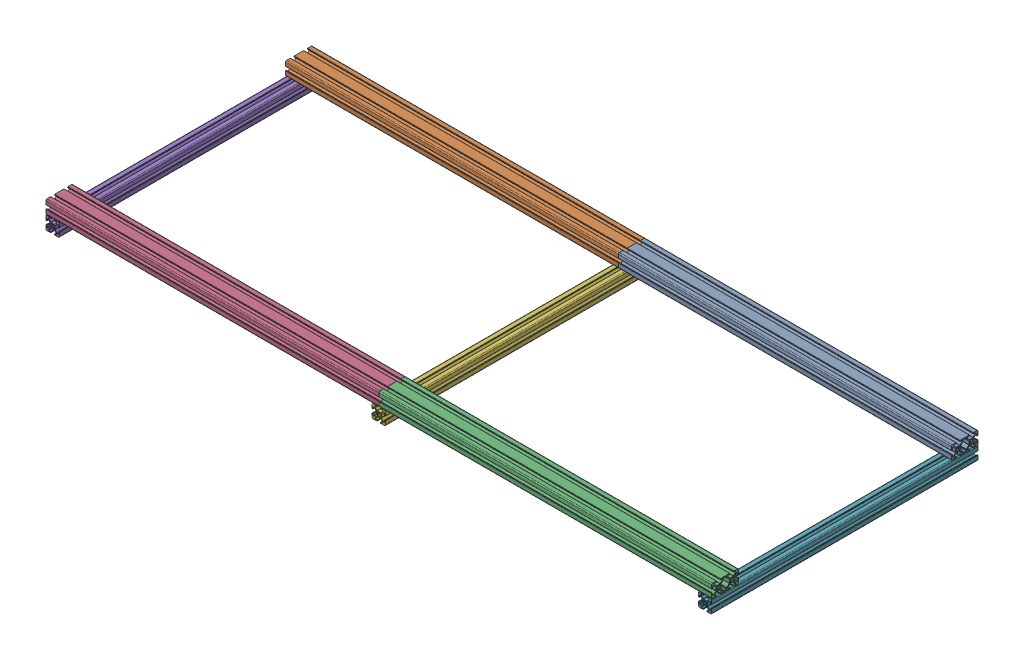
SolidWorks assembly BeltyV2-baseSubAssem, configuration Default. Lengths in mm.
Overall size (1000 40 400).
9 component instances, 2 part files, 16 mates.
Components (placement in the parent):
- BeltyV2-doubleSubAssem-1: BeltyV2-doubleSubAssem [Default] at (253.5332 30.8099 -182.4146) size (1000 20 40)
  - 2040-50-1: 2040-50 [Default] at (246.4668 -0.8099 2.4146) size (500 20 40)
  - 2040-50-2: 2040-50 [Default] at (-253.5332 -0.8099 2.4146) size (500 20 40)
- BeltyV2-doubleSubAssem-2: BeltyV2-doubleSubAssem [Default] at (253.5332 30.8099 177.5854) size (1000 20 40)
  - 2040-50-1: 2040-50 [Default] at (246.4668 -0.8099 2.4146) size (500 20 40)
  - 2040-50-2: 2040-50 [Default] at (-253.5332 -0.8099 2.4146) size (500 20 40)
- 2020-41-1: 2020-41 [Default] at (-490 10 200) x (0 0 1) z (-1 0 0) size (400 20 20)
- 2020-41-2: 2020-41 [Default] at (0 10 200) x (0 0 1) z (-1 0 0) size (400 20 20)
- 2020-41-3: 2020-41 [Default] at (490 10 -200) x (0 0 -1) z (0 1 0) size (400 20 20)
Mates (geometry in assembly coordinates):
- Coincident1: coincident aligned: plane of BeltyV2-doubleSubAssem-2/2040-50-2 through (0 35.819 74.8194) normal (0 0 1); plane of 2020-40-1 through (-490 10 74.8194) normal (0 0 1)
- Coincident2: coincident anti-aligned: plane of BeltyV2-doubleSubAssem-2/2040-50-2 through (0 20 54.8194) normal (0 -1 0); plane of 2020-40-1 through (-484.181 20 74.8194) normal (0 1 0)
- Coincident3: coincident aligned: plane of BeltyV2-doubleSubAssem-2/2040-50-2 through (-500 30 54.8194) normal (-1 0 0); plane of 2020-40-1 through (-500 15.819 74.8194) normal (-1 0 0)
- Coincident4: coincident aligned: plane of BeltyV2-doubleSubAssem-1/2040-50-2 through (-500 30 -305.1806) normal (-1 0 0); plane of 2020-40-1 through (-500 15.819 74.8194) normal (-1 0 0)
- Coincident5: coincident anti-aligned: plane of BeltyV2-doubleSubAssem-1/2040-50-2 through (0 20 -305.1806) normal (0 -1 0); plane of 2020-40-1 through (-495.819 20 74.8194) normal (0 1 0)
- Coincident6: coincident aligned: plane of BeltyV2-doubleSubAssem-1/2040-50-2 through (-500 30 -305.1806) normal (-1 0 0); plane of 2020-40-1 through (-500 15.819 74.8194) normal (-1 0 0)
- Coincident7: coincident aligned: plane of BeltyV2-doubleSubAssem-1/2040-50-2 through (0 24.181 -325.1806) normal (0 0 -1); plane of 2020-40-1 through (-490 10 -325.1806) normal (0 0 -1)
- Coincident8: coincident aligned: plane of BeltyV2-doubleSubAssem-2/2040-50-2 through (0 35.819 200) normal (0 0 1); plane of 2020-40-2 through (0 10 200) normal (0 0 1)
- Coincident9: coincident: line of BeltyV2-doubleSubAssem-1/2040-50-1 through (0 40 -193.138) axis (0 0 -1); plane of 2020-40-2 through (0 10 200) normal (-1 0 0)
- Coincident10: coincident anti-aligned: plane of BeltyV2-doubleSubAssem-2/2040-50-1 through (500 20 180) normal (0 -1 0); plane of 2020-40-2 through (5.819 20 200) normal (0 1 0)
- Coincident11: coincident anti-aligned: plane of 2020-40-2 through (0 10 200) normal (-1 0 0)
- Coincident12: coincident anti-aligned: plane of 2020-40-2 through (-5.819 0 200) normal (0 -1 0)
- Distance1: distance = 200 mm: plane of 2020-40-2 through (0 10 200) normal (0 0 1)
- Coincident14: coincident: plane of BeltyV2-doubleSubAssem-1/2040-50-1 through (500 35.819 -200) normal (0 0 -1); plane of 2020-40-3 through (490 10 -200) normal (0 0 -1)
- Coincident15: coincident: plane of BeltyV2-doubleSubAssem-1/2040-50-1 through (500 20 -180) normal (0 -1 0); plane of 2020-40-3 through (484.181 20 -200) normal (0 1 0)
- Coincident16: coincident aligned: plane of 2020-40-3 through (500 15.819 -200) normal (1 0 0); plane of BeltyV2-doubleSubAssem-1/2040-50-1 through (500 30 -180) normal (1 0 0)
